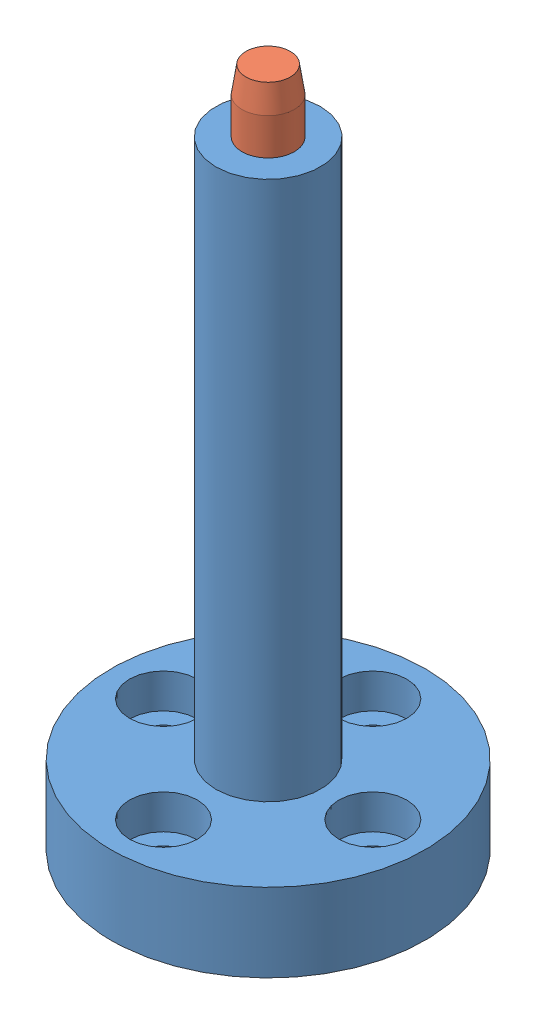
SolidWorks assembly assemb_pino_posi_t2, configuration Default. Lengths in mm.
Overall size (60 130.34 60).
3 component instances, 3 part files, 4 mates.
Components (placement in the parent):
- suporte_posi_t2-1: suporte_posi_t2 [Default] at (49.445 2.9845 87.4507) size (60 118 60)
- pino_t2-1: pino_t2 [Default] at (49.445 54.9845 87.4507) size (14.5 78 14.5)
- mola_posicionamento-1: mola_posicionamento [Default] at (49.445 54.9845 87.4507) x (-0.837169 0 -0.546944) z (-0.546944 0 0.837169) size (14.66 52.36 14.64)
Mates (geometry in assembly coordinates):
- Concentric1: concentric anti-aligned: cylinder of suporte_posi_t2-1 through (49.445 120.9845 87.4507) axis (0 -1 0) radius 10; cylinder of pino_t2-1 through (49.445 132.9845 87.4507) axis (0 1 0) radius 5
- Coincident1: coincident anti-aligned: plane of suporte_posi_t2-1 through (49.445 59.9845 87.4507) normal (0 -1 0); plane of pino_t2-1 through (56.695 59.9845 87.4507) normal (0 1 0)
- Concentric2: concentric aligned: cylinder of suporte_posi_t2-1 through (49.445 59.9845 87.4507) axis (0 -1 0) radius 7.25; circle of mola_posicionamento-1
- Coincident2: coincident aligned: plane of pino_t2-1 through (49.445 54.9845 87.4507) normal (0 -1 0); circle of mola_posicionamento-1
